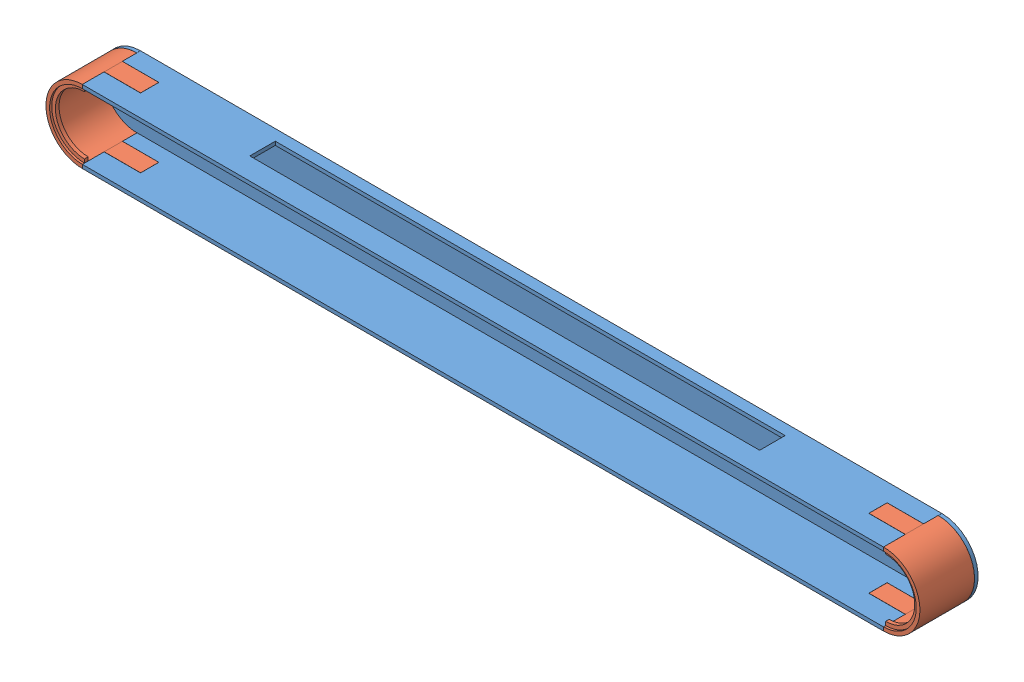
SolidWorks assembly frame, configuration Default. Lengths in mm.
Overall size (1200 100 80.05).
3 component instances, 2 part files, 6 mates.
Components (placement in the parent):
- joint-1: joint [Default] at (204.0141 760.523 893.6313) size (1200 100 80)
- joint-sides-1: joint-sides [Default] at (203.9641 760.523 893.5813) size (100 100 75)
- joint-sides-2: joint-sides [Default] at (298.6966 760.523 893.6813) x (-1 0 0) z (0 0 1) size (100 100 75)
Mates (geometry in assembly coordinates):
- Distance2: distance = 0.05 mm anti-aligned: plane of joint-1 through (-248.5196 710.523 943.8313) normal (-1 0 0); plane of joint-sides-2 through (-248.5696 760.523 893.6813) normal (1 0 0)
- Distance4: distance = 0.05 mm anti-aligned: plane of joint-sides-2 through (-248.5696 805.523 918.6813) normal (0 0 -1); plane of joint-1 through (-248.7196 810.523 918.6313) normal (0 0 1)
- Tangent4: tangent aligned: plane of joint-1 through (-298.7196 810.523 973.6313) normal (0 1 0); cylinder of joint-sides-2 through (-298.5696 760.523 973.6813) axis (0 0 -1) radius 50
- Distance6: distance = 0.05 mm: plane of joint-sides-1 through (751.2304 760.523 893.5813) normal (-1 0 0); plane of joint-1 through (751.1804 710.523 918.5313) normal (1 0 0)
- Distance7: distance = 0.05 mm: plane of joint-sides-1 through (751.2304 810.523 918.5813) normal (0 0 -1); plane of joint-1 through (751.1804 710.523 918.5313) normal (0 0 1)
- Coincident10: coincident aligned: plane of joint-1 through (-298.7196 810.523 973.6313) normal (0 1 0); plane of joint-sides-1 through (751.2304 810.523 918.5813) normal (0 1 0)
